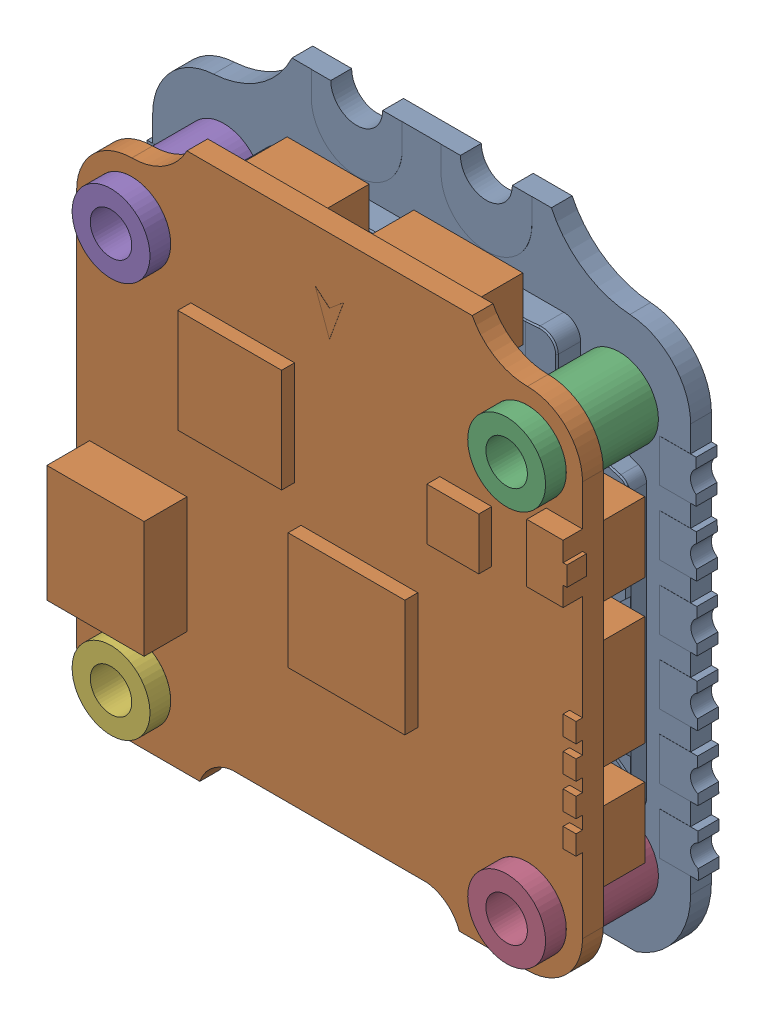
SolidWorks assembly SpeedyBee, configuration Default. Lengths in mm.
Overall size (42.67 46.4 16).
2 component instances, 2 part files, 3 mates.
Components (placement in the parent):
- SPF455A 4in1 ESC-1: SPF455A 4in1 ESC [Default] at (-3.9399 -0.5425 1.6839) size (42.67 46.4 7.6)
- Speedybee F7V3-2: Speedybee F7V3 [Default] at (-3.9399 -2.9422 9.9839) x (-1 0 0) z (0 0 1) size (39.3 41.6 10.4)
Mates (geometry in assembly coordinates):
- Coincident1: coincident: plane of SPF455A 4in1 ESC-1 through (-3.9399 -0.8922 4.4839) normal (0 0 1); plane of Speedybee F7V3-2 through (-49.6899 -48.6922 4.4839) normal (0 0 -1)
- Concentric3: concentric: circle of SPF455A 4in1 ESC-1; circle of Speedybee F7V3-2
- Concentric4: concentric aligned: circle of SPF455A 4in1 ESC-1; circle of Speedybee F7V3-2
